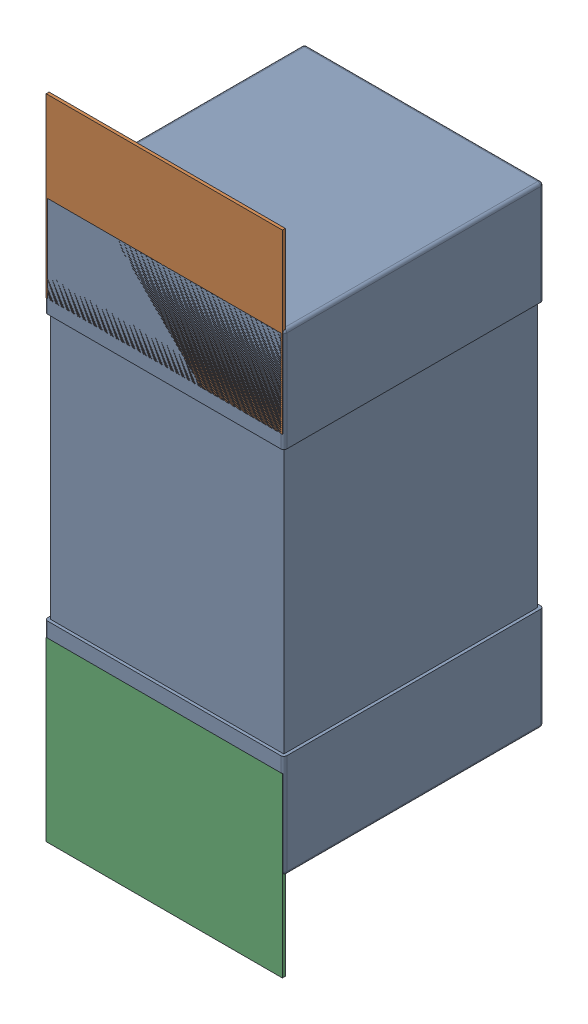
SolidWorks assembly C112, configuration Défaut. Lengths in mm.
Overall size (0.81 2.19 0.88).
5 component instances, 2 part files, 0 mates.
Components (placement in the parent):
- 0603_C-1: 0603_C [Défaut] at (5.146 -8.5544 -2.0818) x (0 -1 0) z (0 0 -1) size (1.6 0.81 0.88)
- 8260087904-1: 8260087904 [Défaut] at (5.146 -8.2095 -2.0918) size (0.8 0.6 0.01)
  - Extruded_1211-1: Extruded_1211 [Défaut] at origin size (0.8 0.6 0.01)
- 8260087904-2: 8260087904 [Défaut] at (5.146 -9.8044 -2.0918) size (0.8 0.6 0.01)
  - Extruded_1211-1: Extruded_1211 [Défaut] at origin size (0.8 0.6 0.01)
